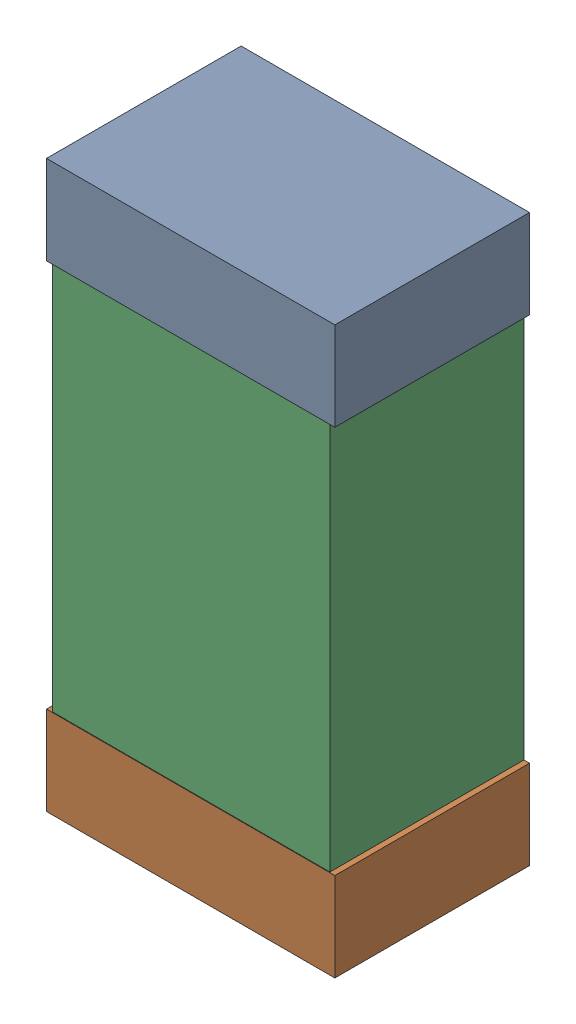
SolidWorks assembly R27, configuration Default. Lengths in mm.
Overall size (0.52 1.02 0.35).
6 component instances, 2 part files, 0 mates.
Components (placement in the parent):
- 870941120-1: 870941120 [Default] at (50.038 9.193 0) size (0.52 0.16 0.35)
  - Extruded_3-1: Extruded_3 [Default] at origin size (0.52 0.16 0.35)
- 870941120-2: 870941120 [Default] at (50.038 8.333 0) size (0.52 0.16 0.35)
  - Extruded_3-1: Extruded_3 [Default] at origin size (0.52 0.16 0.35)
- 870941280-1: 870941280 [Default] at (50.038 8.763 0) size (0.5 1 0.35)
  - Extruded_4-1: Extruded_4 [Default] at origin size (0.5 1 0.35)
